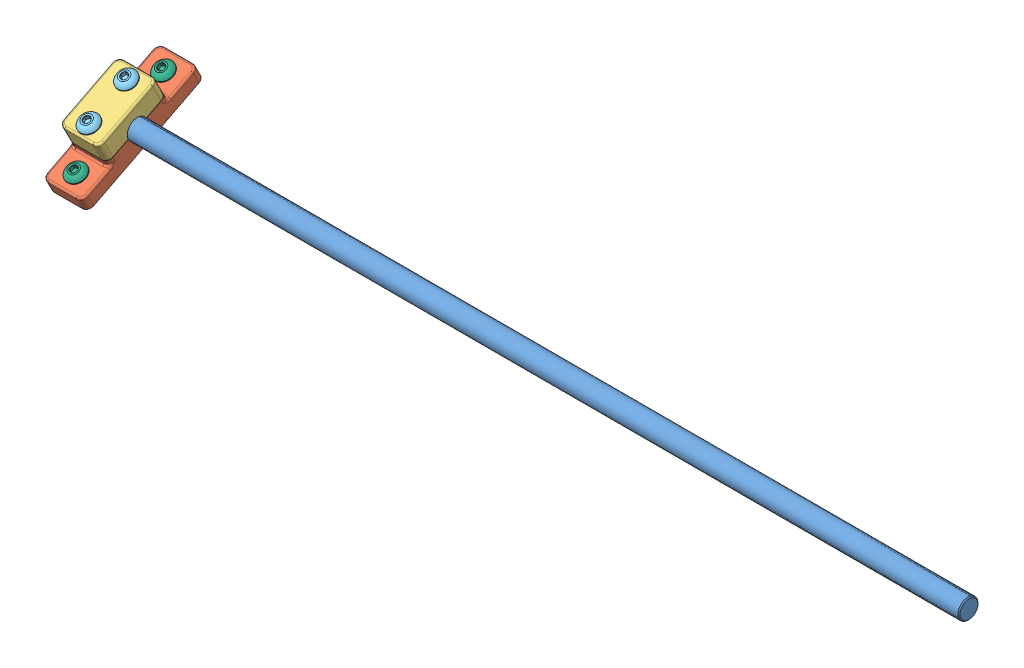
SolidWorks assembly Z_Rod_And_Mounts, configuration Default. Lengths in mm.
Overall size (435.2 45.93 63.52).
11 component instances, 7 part files, 25 mates.
Components (placement in the parent):
- SFJ10-435-1: SFJ10-435 [Default] at origin size (435 10 10)
- Z_Axis_Shaft_Mount_A-1: Z_Axis_Shaft_Mount_A [Default] at (10 -8.9054 -4.549) x (0 0.4549 -0.890543) z (1 0 0) size (65 10 20.4)
- Z_Axis_Shaft_Mount_B-2: Z_Axis_Shaft_Mount_B [Default] at (10 9.0835 4.64) x (0 -0.4549 0.890543) z (1 0 0) size (33 10 20)
- 5mm_Hex_NyLockNut(McMaster_94205A240)-4: 5mm_Hex_NyLockNut(McMaster_94205A240) [94205A240] at (10 0.3237 -11.6252) x (0.866025 0.22745 -0.445271) z (-0.5 0.393955 -0.771233) size (8 5.15 9.24)
- 5mm_Hex_NyLockNut(McMaster_94205A240)-3: 5mm_Hex_NyLockNut(McMaster_94205A240) [94205A240] at (10 -9.2292 7.0762) x (-0.866025 -0.22745 0.445271) z (0.5 -0.393955 0.771233) size (8 5.15 9.24)
- 5mmX20mm_Buttonhead(McMaster_92095A214)-5: 5mmX20mm_Buttonhead(McMaster_92095A214) [91239A232] at (10 16.309 -3.4597) x (0.038834 -0.454557 0.889871) z (0 0.890543 0.4549) size (9.5 9.5 23.26)
- 5mmX20mm_Buttonhead(McMaster_92095A214)-4: 5mmX20mm_Buttonhead(McMaster_92095A214) [91239A232] at (10 6.7561 15.2416) x (-0.219514 -0.443804 0.868822) z (0 0.890543 0.4549) size (9.5 9.5 23.26)
- 5mmX12mm_Buttonhead(McMaster_92095A210)-9: 5mmX12mm_Buttonhead(McMaster_92095A210) [92095A210] at (10 -11.3677 21.7046) x (0.994775 -0.046442 0.090918) z (0 0.890543 0.4549) size (9.5 9.5 15.22)
- 5mmX12mm_Buttonhead(McMaster_92095A210)-8: 5mmX12mm_Buttonhead(McMaster_92095A210) [92095A210] at (10 10.9224 -21.932) x (-0.512081 -0.39073 0.76492) z (0 0.890543 0.4549) size (9.5 9.5 15.22)
- HNTTSN5-5-1: HNTTSN5-5 [Default] at (10 1.171 -26.9132) x (0 0.890543 0.4549) z (0 -0.4549 0.890543) size (4.3 10 10)
- HNTTSN5-5-2: HNTTSN5-5 [Default] at (10 -21.1191 16.7234) x (0 0.890543 0.4549) z (0 -0.4549 0.890543) size (4.3 10 10)
Mates (geometry in assembly coordinates):
- Coincident5: coincident anti-aligned: plane of Z_Axis_Shaft_Mount_A-1 through (10 -4.4527 -2.2745) normal (0 -0.890543 -0.4549); plane of 5mm_Hex_NyLockNut(McMaster_94205A240)-3 through (10 -5.59 -0.0481) normal (0 0.890543 0.4549)
- Parallel3: parallel aligned: plane of Z_Axis_Shaft_Mount_A-1 through (12.3094 -7.4096 3.514) normal (-0.866025 -0.22745 0.445271); plane of 5mm_Hex_NyLockNut(McMaster_94205A240)-3 through (7.6906 -15.5015 8.3639) normal (-0.866025 -0.22745 0.445271)
- Concentric3: concentric anti-aligned: cylinder of Z_Axis_Shaft_Mount_A-1 through (10 -7.4481 7.986) axis (0 -0.890543 -0.4549) radius 2.6; cylinder of 5mm_Hex_NyLockNut(McMaster_94205A240)-3 through (10 -13.0076 5.1461) axis (0 0.890543 0.4549) radius 2.1277
- Coincident7: coincident anti-aligned: plane of Z_Axis_Shaft_Mount_A-1 through (10 -4.4527 -2.2745) normal (0 -0.890543 -0.4549); plane of 5mm_Hex_NyLockNut(McMaster_94205A240)-4 through (10 -3.3155 -4.5009) normal (0 0.890543 0.4549)
- Parallel4: parallel aligned: plane of Z_Axis_Shaft_Mount_A-1 through (12.3094 2.1433 -15.1874) normal (-0.866025 -0.22745 0.445271); plane of 5mm_Hex_NyLockNut(McMaster_94205A240)-4 through (7.6906 -5.9486 -10.3375) normal (-0.866025 -0.22745 0.445271)
- Concentric4: concentric anti-aligned: cylinder of Z_Axis_Shaft_Mount_A-1 through (10 2.1048 -10.7154) axis (0 -0.890543 -0.4549) radius 2.6; cylinder of 5mm_Hex_NyLockNut(McMaster_94205A240)-4 through (10 -3.4547 -13.5553) axis (0 0.890543 0.4549) radius 2.1277
- Coincident11: coincident aligned: plane of Z_Axis_Shaft_Mount_A-1 through (0 -16.0912 24.9063) normal (-1 0 0); plane of Z_Axis_Shaft_Mount_B-2 through (0 6.3193 -11.9313) normal (-1 0 0)
- Concentric6: concentric anti-aligned: cylinder of Z_Axis_Shaft_Mount_A-1 through (10 -7.4481 7.986) axis (0 -0.890543 -0.4549) radius 2.6; cylinder of Z_Axis_Shaft_Mount_B-2 through (10 -4.5983 9.4417) axis (0 0.890543 0.4549) radius 2.6
- Distance2: distance = 0.2 mm anti-aligned: plane of Z_Axis_Shaft_Mount_B-2 through (17 6.3193 -11.9313) normal (0 -0.890543 -0.4549); plane of Z_Axis_Shaft_Mount_A-1 through (3 6.1411 -12.0223) normal (0 0.890543 0.4549)
- Concentric7: concentric anti-aligned: cylinder of SFJ10-435-1 through (435 0 0) axis (-1 0 0) radius 5; cylinder of Z_Axis_Shaft_Mount_A-1 through (-14.1421 0 0) axis (1 0 0) radius 5
- Coincident13: coincident aligned: plane of SFJ10-435-1 through (0 0 0) normal (-1 0 0); plane of Z_Axis_Shaft_Mount_A-1 through (0 -16.0912 24.9063) normal (-1 0 0)
- Concentric101: concentric aligned: cylinder of Z_Axis_Shaft_Mount_B-2 through (10 4.9546 -9.2597) axis (0 0.890543 0.4549) radius 2.6; cylinder of 5mmX20mm_Buttonhead(McMaster_92095A214)-5 through (10 16.309 -3.4597) axis (0 0.890543 0.4549) radius 4.75
- Coincident171: coincident anti-aligned: plane of Z_Axis_Shaft_Mount_B-2 through (17 15.2247 -7.3823) normal (0 0.890543 0.4549); plane of 5mmX20mm_Buttonhead(McMaster_92095A214)-5 through (5.2536 13.7761 -4.5464) normal (0 -0.890543 -0.4549)
- Concentric111: concentric aligned: cylinder of Z_Axis_Shaft_Mount_B-2 through (10 -4.5983 9.4417) axis (0 0.890543 0.4549) radius 2.6; cylinder of 5mmX20mm_Buttonhead(McMaster_92095A214)-4 through (10 6.7561 15.2416) axis (0 0.890543 0.4549) radius 4.75
- Coincident181: coincident anti-aligned: plane of Z_Axis_Shaft_Mount_B-2 through (17 15.2247 -7.3823) normal (0 0.890543 0.4549); plane of 5mmX20mm_Buttonhead(McMaster_92095A214)-4 through (5.3659 4.7814 13.0621) normal (0 -0.890543 -0.4549)
- Concentric1321: concentric anti-aligned: cylinder of Z_Axis_Shaft_Mount_A-1 through (10 -13.8167 20.4536) axis (0 -0.890543 -0.4549) radius 2.6; cylinder of 5mmX12mm_Buttonhead(McMaster_92095A210)-9 through (10 -11.3677 21.7046) axis (0 0.890543 0.4549) radius 4.75
- Coincident2021: coincident anti-aligned: plane of Z_Axis_Shaft_Mount_A-1 through (17 -16.0912 24.9063) normal (0 0.890543 0.4549); plane of 5mmX12mm_Buttonhead(McMaster_92095A210)-9 through (9.5151 -15.9662 24.6616) normal (0 -0.890543 -0.4549)
- Concentric1331: concentric anti-aligned: cylinder of Z_Axis_Shaft_Mount_A-1 through (10 8.4734 -23.183) axis (0 -0.890543 -0.4549) radius 2.6; cylinder of 5mmX12mm_Buttonhead(McMaster_92095A210)-8 through (10 10.9224 -21.932) axis (0 0.890543 0.4549) radius 4.75
- Coincident2031: coincident anti-aligned: plane of Z_Axis_Shaft_Mount_A-1 through (17 -16.0912 24.9063) normal (0 0.890543 0.4549); plane of 5mmX12mm_Buttonhead(McMaster_92095A210)-8 through (5.92 9.5799 -25.3491) normal (0 -0.890543 -0.4549)
- Concentric138: concentric anti-aligned: cylinder of 5mmX12mm_Buttonhead(McMaster_92095A210)-9 through (10 -11.3677 21.7046) axis (0 0.890543 0.4549) radius 4.75; cylinder of HNTTSN5-5-2 through (10 -21.1191 16.7234) axis (0 -0.890543 -0.4549) radius 2.067
- Parallel8: parallel aligned: plane of Z_Axis_Shaft_Mount_A-1 through (17 -17.4559 27.5779) normal (0 -0.4549 0.890543); plane of HNTTSN5-5-2 through (10 -23.3936 21.1761) normal (0 -0.4549 0.890543)
- Concentric139: concentric anti-aligned: cylinder of 5mmX12mm_Buttonhead(McMaster_92095A210)-8 through (10 10.9224 -21.932) axis (0 0.890543 0.4549) radius 4.75; cylinder of HNTTSN5-5-1 through (10 1.171 -26.9132) axis (0 -0.890543 -0.4549) radius 2.067
- Parallel9: parallel aligned: plane of Z_Axis_Shaft_Mount_A-1 through (17 -17.4559 27.5779) normal (0 -0.4549 0.890543); plane of HNTTSN5-5-1 through (10 -1.1035 -22.4605) normal (0 -0.4549 0.890543)
- Distance3: distance = 2 mm anti-aligned: plane of Z_Axis_Shaft_Mount_A-1 through (17 -22.325 21.722) normal (0 -0.890543 -0.4549); plane of HNTTSN5-5-2 through (7.1 -24.1061 20.8122) normal (0 0.890543 0.4549)
- Distance4: distance = 2 mm anti-aligned: plane of Z_Axis_Shaft_Mount_A-1 through (17 -22.325 21.722) normal (0 -0.890543 -0.4549); plane of HNTTSN5-5-1 through (7.1 -1.816 -22.8244) normal (0 0.890543 0.4549)
